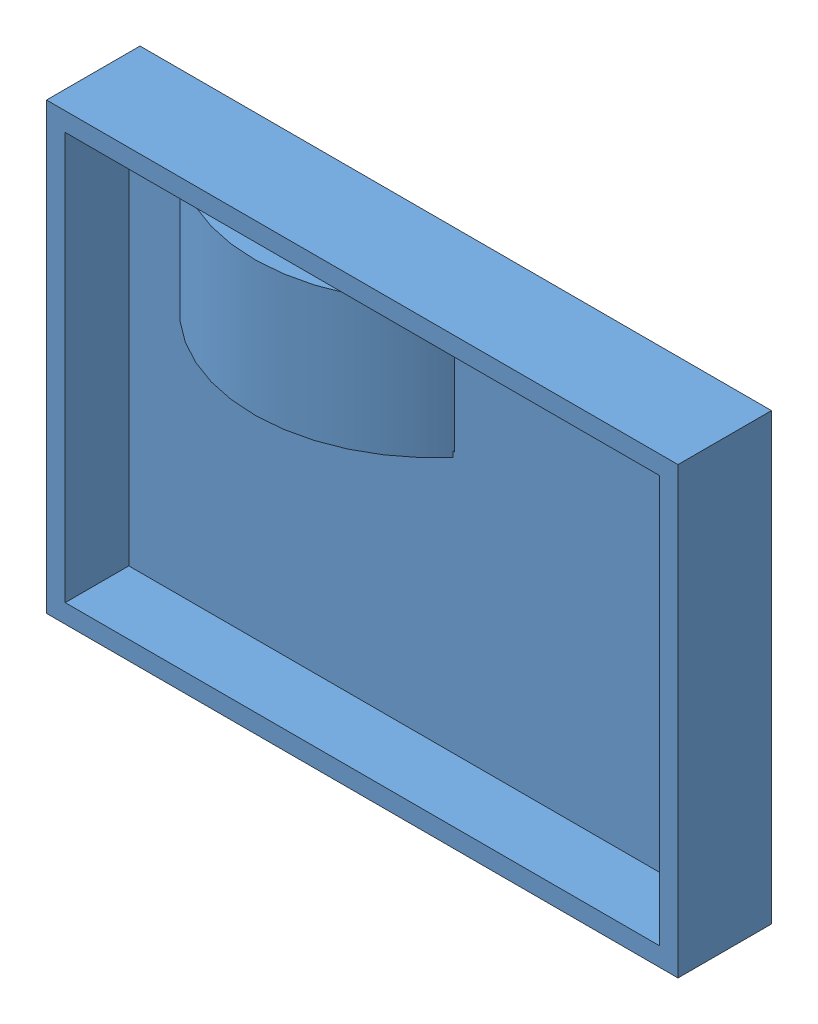
SolidWorks assembly Assem1, configuration Default. Lengths in mm.
Overall size (168.81 118.86 25).
2 component instances, 2 part files, 3 mates.
Components (placement in the parent):
- Part2-1: Part2 [Default] at (160.5514 36.152 113.3945) size (168.81 118.86 25)
- basebot-1: basebot [Default] at (160.5514 36.152 113.3945) x (-1 0 0) z (0 -1 0) size (118.57 5 59.18)
Mates (geometry in assembly coordinates):
- Coincident1: coincident: line of Part2-1 through (84.3857 95.3359 113.3945) axis (-1 0 0); line of basebot-1 through (46.4248 95.3359 113.3945) axis (1 0 0)
- Coincident2: coincident: plane of Part2-1 through (160.5514 36.152 113.3945) normal (0 0 -1); plane of basebot-1 through (160.5514 36.152 113.3945) normal (0 0 1)
- Coincident3: coincident anti-aligned: line of Part2-1 through (46.4248 95.3359 113.3945) axis (0 -1 0); line of basebot-1 through (46.4248 36.152 113.3945) axis (0 1 0)
